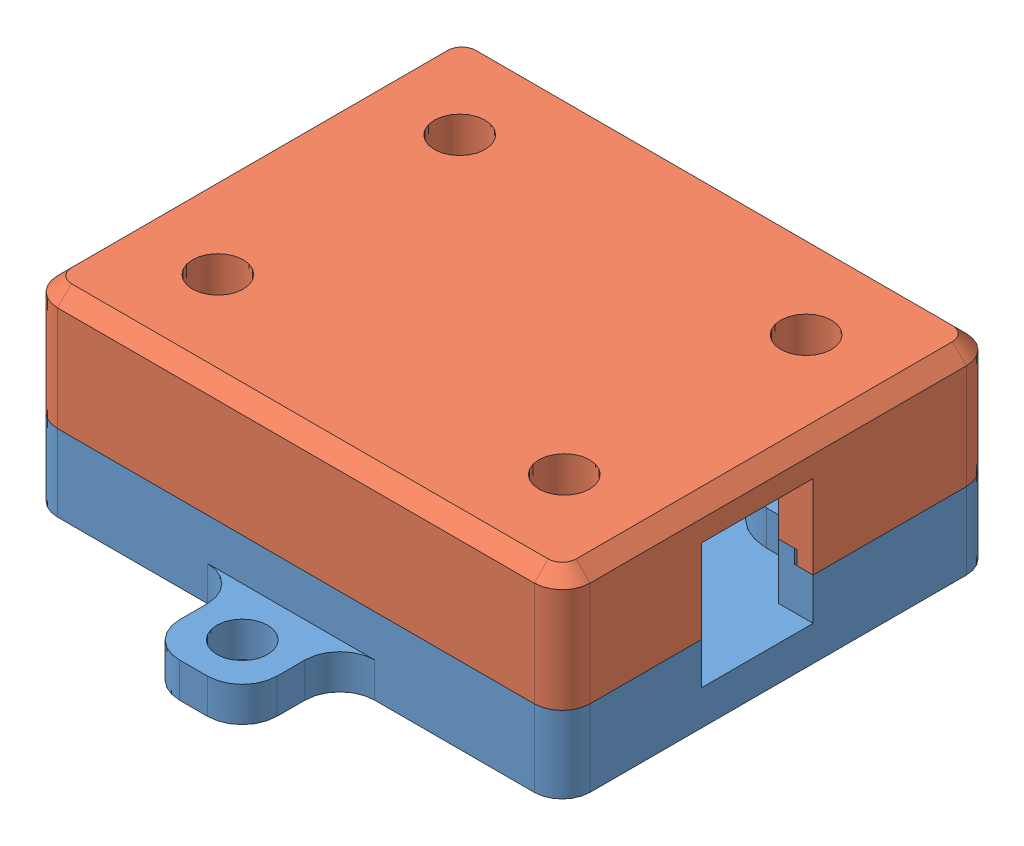
SolidWorks assembly PCB Shroud Assembly, configuration Default. Lengths in mm.
Overall size (38.2 14 45).
2 component instances, 2 part files, 4 mates.
Components (placement in the parent):
- PCB Shroud-1: PCB Shroud [Default] at origin size (38.2 6.5 45)
- PCB Shroud Top-1: PCB Shroud Top [Default] at (0 14 0) x (1 0 0) z (0 0 -1) size (38.2 8.5 31)
Mates (geometry in assembly coordinates):
- Coincident1: coordinate: point of PCB Shroud-1
- Coincident2: coincident aligned: plane of PCB Shroud-1 through (19.1 5.5 13.5) normal (1 0 0); plane of PCB Shroud Top-1 through (19.1 6.5 -13.5) normal (1 0 0)
- Coincident3: coincident aligned: plane of PCB Shroud-1 through (-17.1 5.5 15.5) normal (0 0 1); plane of PCB Shroud Top-1 through (-17.1 6.5 15.5) normal (0 0 1)
- Coincident4: coincident anti-aligned: plane of PCB Shroud-1 through (17.1 5.5 -13.5) normal (0 1 0); plane of PCB Shroud Top-1 through (-17.1 5.5 13.5) normal (0 -1 0)
